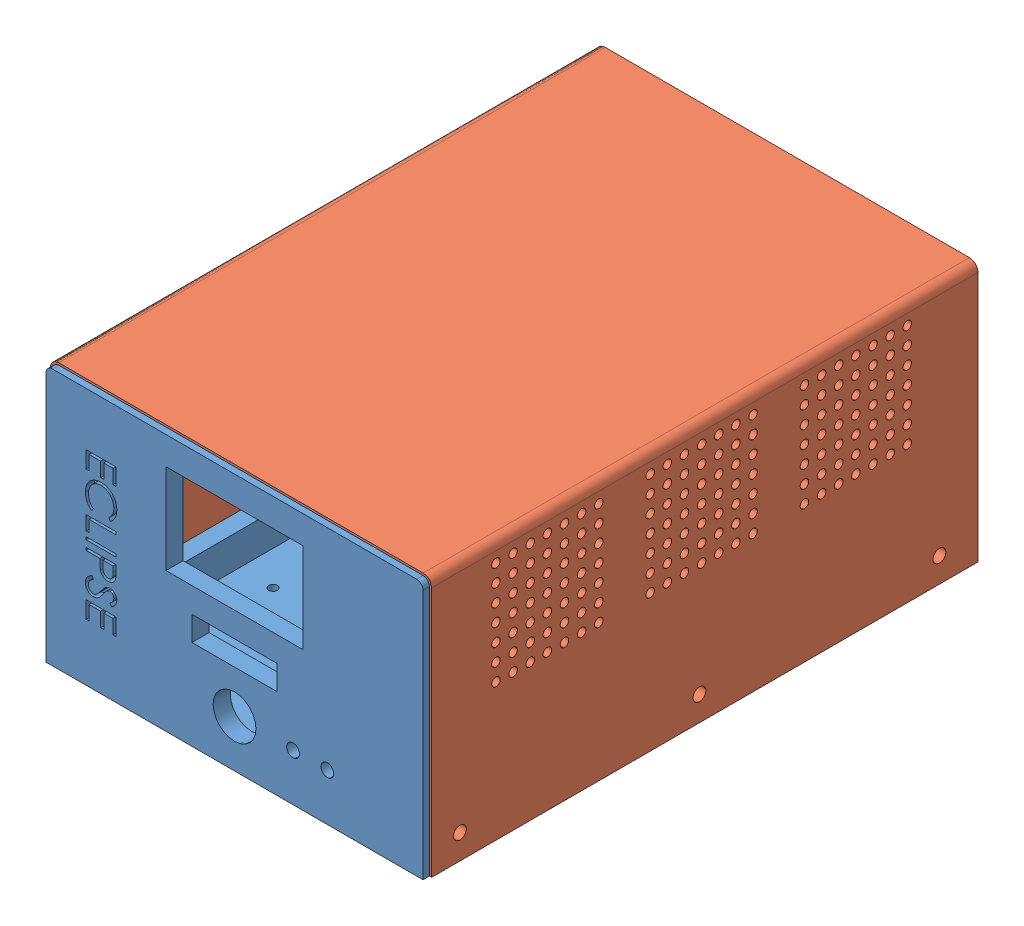
SolidWorks assembly Assemble_final, configuration Default. Lengths in mm.
Overall size (89 60.5 129).
2 component instances, 2 part files, 3 mates.
Components (placement in the parent):
- part1-1: part1 [Default] at (-44.6823 11.7964 80.064) size (88 60 129)
- Part2(New)-1: Part2(New) [Default] at (-44.6823 12.0464 -48.936) x (0 0 1) z (-1 0 0) size (127.5 60.5 89)
Mates (geometry in assembly coordinates):
- Coincident1: coincident aligned: plane of part1-1 through (-0.6823 -18.2036 78.564) normal (0 -1 0); plane of Part2(New)-1 through (-0.1823 -18.2036 78.564) normal (0 -1 0)
- Coincident2: coincident anti-aligned: plane of part1-1 through (-44.6823 11.7964 78.564) normal (0 0 -1); plane of Part2(New)-1 through (-44.6823 12.0464 78.564) normal (0 0 1)
- Coincident3: coincident anti-aligned: plane of part1-1 through (-2.6823 39.7964 -48.936) normal (1 0 0); plane of Part2(New)-1 through (-2.6823 -18.2036 78.564) normal (-1 0 0)
